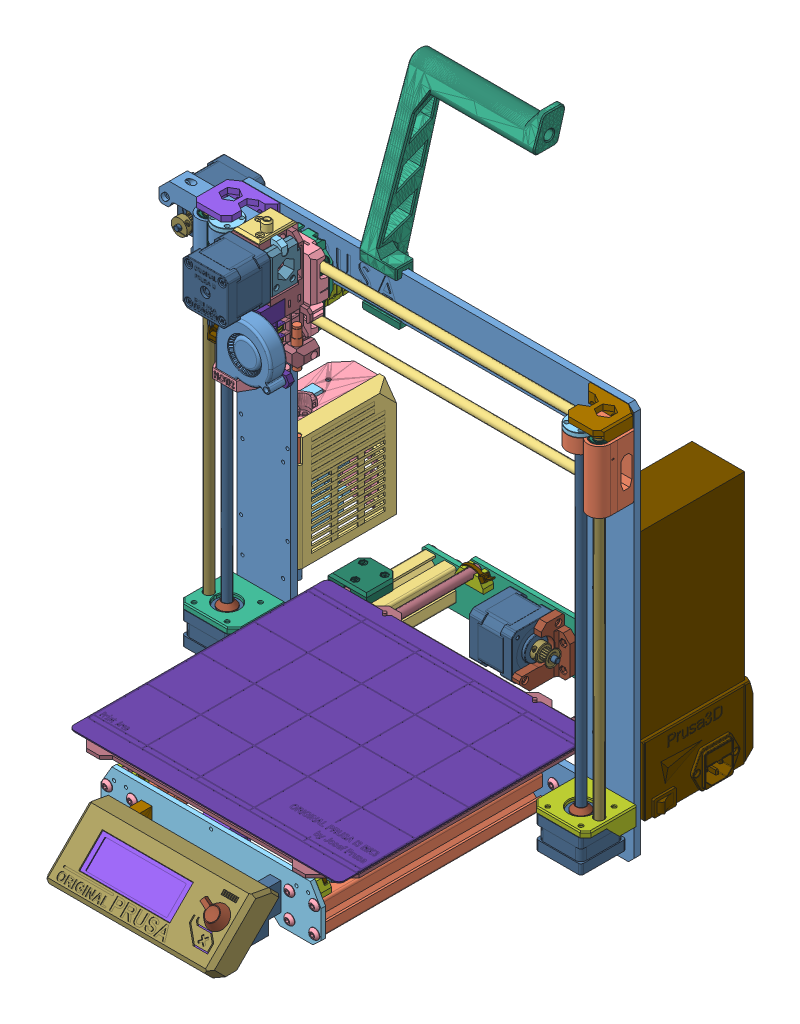
SolidWorks assembly Prusa i3 MK3, configuration Default. Lengths in mm.
Overall size (428.7 559.98 435.12).
133 component instances, 60 part files, 144 mates.
Components (placement in the parent):
- Frame Assembly-1: Frame Assembly [Default] at (46.7331 -29.8101 -38.614) size (370 375 345.6)
  - i3 MK3 Frame-1: i3 MK3 Frame [Default] at (-79.4742 52.1894 268.1135) size (370 370 6.25)
  - Long Extrusion-1: Long Extrusion [Default] at (190.5258 68.6894 274.3635) size (30 30 205)
  - Long Extrusion-2: Long Extrusion [Default] at (20.5258 68.6894 274.3635) size (30 30 205)
  - Short Extrusion-1: Short Extrusion [Default] at (-16.4742 68.6894 148.1135) size (30 30 120)
  - Short Extrusion-2: Short Extrusion [Default] at (227.5258 68.6894 148.1135) size (30 30 120)
  - M5-16 Caphead Screw-1: M5-16 Caphead Screw [92095A212] at (239.1258 57.0894 277.1135) size (9.5 9.5 19.24)
  - M5-16 Caphead Screw-2: M5-16 Caphead Screw [92095A212] at (8.9287 80.3027 486.3635) size (9.5 9.5 19.24)
  - M5-16 Caphead Screw-3: M5-16 Caphead Screw [92095A212] at (202.1295 80.303 486.3635) size (9.5 9.5 19.24)
  - M5-16 Caphead Screw-4: M5-16 Caphead Screw [92095A212] at (178.9311 80.3021 486.3635) size (9.5 9.5 19.24)
  - M5-16 Caphead Screw-5: M5-16 Caphead Screw [92095A212] at (215.9258 80.2894 277.1135) size (9.5 9.5 19.24)
  - M5-16 Caphead Screw-6: M5-16 Caphead Screw [92095A212] at (8.9258 57.0894 486.3635) size (9.5 9.5 19.24)
  - M5-16 Caphead Screw-7: M5-16 Caphead Screw [92095A212] at (178.9324 57.0896 486.3635) size (9.5 9.5 19.24)
  - M5-16 Caphead Screw-8: M5-16 Caphead Screw [92095A212] at (239.1258 80.2894 277.1135) size (9.5 9.5 19.24)
  - M5-16 Caphead Screw-9: M5-16 Caphead Screw [92095A212] at (202.1324 57.0896 486.3635) size (9.5 9.5 19.24)
  - M5-16 Caphead Screw-10: M5-16 Caphead Screw [92095A212] at (32.1258 57.0894 486.3635) size (9.5 9.5 19.24)
  - M5-16 Caphead Screw-11: M5-16 Caphead Screw [92095A212] at (32.127 80.3019 486.3635) size (9.5 9.5 19.24)
  - M5-16 Caphead Screw-12: M5-16 Caphead Screw [92095A212] at (-4.8742 80.2894 277.1135) size (9.5 9.5 19.24)
  - M5-16 Caphead Screw-13: M5-16 Caphead Screw [92095A212] at (-4.8742 57.0894 277.1135) size (9.5 9.5 19.24)
  - M5-16 Caphead Screw-14: M5-16 Caphead Screw [92095A212] at (-28.0742 80.2894 277.1135) size (9.5 9.5 19.24)
  - M5-16 Caphead Screw-15: M5-16 Caphead Screw [92095A212] at (-28.0742 57.0894 277.1135) size (9.5 9.5 19.24)
  - M5-16 Caphead Screw-16: M5-16 Caphead Screw [92095A212] at (215.9258 57.0894 277.1135) size (9.5 9.5 19.24)
  - M5-16 Caphead Screw-17: M5-16 Caphead Screw [92095A212] at (215.9258 80.2894 141.1135) x (1 0 0) z (0 0 -1) size (9.5 9.5 19.24)
  - M5-16 Caphead Screw-18: M5-16 Caphead Screw [92095A212] at (32.1258 80.2894 265.3635) x (1 0 0) z (0 0 -1) size (9.5 9.5 19.24)
  - M5-16 Caphead Screw-19: M5-16 Caphead Screw [92095A212] at (202.1258 80.2894 265.3635) x (1 0 0) z (0 0 -1) size (9.5 9.5 19.24)
  - M5-16 Caphead Screw-20: M5-16 Caphead Screw [92095A212] at (178.9258 80.2894 265.3635) x (1 0 0) z (0 0 -1) size (9.5 9.5 19.24)
  - M5-16 Caphead Screw-21: M5-16 Caphead Screw [92095A212] at (215.926 57.0893 141.1135) x (1 0 0) z (0 0 -1) size (9.5 9.5 19.24)
  - M5-16 Caphead Screw-22: M5-16 Caphead Screw [92095A212] at (8.9258 57.0894 265.3635) x (1 0 0) z (0 0 -1) size (9.5 9.5 19.24)
  - M5-16 Caphead Screw-23: M5-16 Caphead Screw [92095A212] at (8.9258 80.2894 265.3635) x (1 0 0) z (0 0 -1) size (9.5 9.5 19.24)
  - M5-16 Caphead Screw-24: M5-16 Caphead Screw [92095A212] at (239.1258 80.2894 141.1135) x (1 0 0) z (0 0 -1) size (9.5 9.5 19.24)
  - M5-16 Caphead Screw-25: M5-16 Caphead Screw [92095A212] at (239.1259 57.0892 141.1135) x (1 0 0) z (0 0 -1) size (9.5 9.5 19.24)
  - M5-16 Caphead Screw-26: M5-16 Caphead Screw [92095A212] at (-4.8712 80.276 141.1135) x (1 0 0) z (0 0 -1) size (9.5 9.5 19.24)
  - M5-16 Caphead Screw-27: M5-16 Caphead Screw [92095A212] at (-28.0743 80.2892 141.1135) x (1 0 0) z (0 0 -1) size (9.5 9.5 19.24)
  - M5-16 Caphead Screw-28: M5-16 Caphead Screw [92095A212] at (-28.072 57.0752 141.1135) x (1 0 0) z (0 0 -1) size (9.5 9.5 19.24)
  - M5-16 Caphead Screw-29: M5-16 Caphead Screw [92095A212] at (-4.874 57.0894 141.1135) x (1 0 0) z (0 0 -1) size (9.5 9.5 19.24)
  - M5-16 Caphead Screw-30: M5-16 Caphead Screw [92095A212] at (178.9258 57.0894 265.3635) x (1 0 0) z (0 0 -1) size (9.5 9.5 19.24)
  - M5-16 Caphead Screw-31: M5-16 Caphead Screw [92095A212] at (202.1258 57.0894 265.3635) x (1 0 0) z (0 0 -1) size (9.5 9.5 19.24)
  - M5-16 Caphead Screw-32: M5-16 Caphead Screw [92095A212] at (32.1258 57.0894 265.3635) x (1 0 0) z (0 0 -1) size (9.5 9.5 19.24)
  - MK3 Front Plate-1: MK3 Front Plate [Default] at (105.5324 47.1896 479.3635) x (-1 0 0) z (0 0 1) size (205 50 4.25)
  - MK3 Rear Plate-1: MK3 Rear Plate [Default] at (105.526 50.1894 143.8635) size (278 50 4.25)
- y-rod-holder(R2)-1: y-rod-holder(R2) [Default] at (67.2591 53.8793 109.4995) x (-1 0 0) z (0 0 1) size (26 13.5 10)
- y-rod-holder(R2)-2: y-rod-holder(R2) [Default] at (237.2591 53.8793 109.4995) x (-1 -0.000001 0) z (0 0 1) size (26 13.5 10)
- y-rod-holder(R2)-3: y-rod-holder(R2) [Default] at (67.2588 53.8793 440.7495) x (1 0.000003 0) z (0 0 -1) size (26 13.5 10)
- y-rod-holder(R2)-4: y-rod-holder(R2) [Default] at (237.2655 53.8796 440.7495) x (1 0 0) z (0 0 -1) size (26 13.5 10)
- y-belt-idler(R2)-1: y-belt-idler(R2) [Default] at (152.2622 27.3871 440.7495) x (-1 -0.000001 0) z (-0.000001 1 0) size (25 20 35)
- Idler Roller, flat-1: Idler Roller, flat [Default] at (147.9121 49.8871 426.7495) x (0 0 -1) z (1 0.000001 0) size (18 18 8.83)
- NEMA-17 40mm PR-1: NEMA-17 40mm PR [По умолчанию] at (99.2666 46.3725 130.4995) x (0 0 -1) z (0 -1 0) size (42.3 62 51.35)
- y-motor-holder(R2)-1: y-motor-holder(R2) [Default] at (152.2666 20.3725 110.9995) x (-1 0 0) z (0 1 0) size (19 42 47)
- PULLEY_GT2_16T-1: PULLEY_GT2_16T [Default] at (148.5591 46.3725 130.4995) x (0 -0.177583 0.984106) z (-1 0 0) size (14.7 14.7 14.3)
- Y-Smooth Rod-1: Y-Smooth Rod [Default] at (67.2588 64.3793 110.7495) size (8 8 330)
- Frog Assembly-1: Frog Assembly [Default] at (70.8506 199.1097 499.2992) x (1 0 0) z (0 0 -1) size (227 34.1 222)
  - i3 MK3 Frog-1: i3 MK3 Frog [Default] at (-100.0918 124.8902 356.7011) size (227 4.25 222)
  - LM8UU-1: LM8UU [Default] at (166.4082 134.7303 172.4511) x (0 0 -1) z (0.49499 0.868899 0) size (24 15 15)
  - LM8UU-2: LM8UU [Default] at (-3.5918 134.7303 205.9511) x (0 0 -1) z (0.957162 -0.289554 0) size (24 15 15)
  - LM8UU-3: LM8UU [Default] at (-3.5918 134.7303 135.9511) x (0 0 -1) z (-0.936768 -0.349951 0) size (24 15 15)
  - y-belt-holder(R2)-1: y-belt-holder(R2) [Default] at (88.4082 141.6402 171.2011) x (0 -1 0) z (-1 0 0) size (23.5 48 14)
  - U Bolt-1: U Bolt [Default] at (166.4082 118.7303 171.7011) size (23.09 26.7 3.46)
  - U Bolt-2: U Bolt [Default] at (-3.5918 118.7303 136.7011) size (23.09 26.7 3.46)
  - U Bolt-3: U Bolt [Default] at (-3.5918 118.7303 206.7011) size (23.09 26.7 3.46)
- Y-Smooth Rod-2: Y-Smooth Rod [Default] at (237.2655 64.3796 110.7495) size (8 8 330)
- Y Holder Ziptie-1: Y Holder Ziptie [Default] at (237.2655 53.8796 434.0495) size (30.19 10 6)
- Y Holder Ziptie-2: Y Holder Ziptie [Default] at (237.1042 53.8796 116.1995) x (1 0.000001 0) z (0 0 1) size (30.19 10 6)
- Y Holder Ziptie-3: Y Holder Ziptie [Default] at (67.4135 53.8793 434.0495) x (-1 -0.000003 0) z (0 0 -1) size (30.19 10 6)
- Y Holder Ziptie-4: Y Holder Ziptie [Default] at (67.2591 53.8793 116.1995) x (-1 0 0) z (0 0 -1) size (30.19 10 6)
- x_end_motor_R2_part-1: x_end_motor_R2_part [Default] at (-29.7411 380.6793 265.0495) x (0 0 1) z (0 -1 0) size (36.12 82.62 58)
- x-end-idler(R2)-1: x-end-idler(R2) [Default] at (355.2589 380.6793 265.0495) x (0 0 1) z (0 -1 0) size (36.12 40.12 58)
- X-Smooth Rod-1: X-Smooth Rod [Default] at (-36.7411 374.6793 250.0495) x (0 0 -1) z (1 0 0) size (8 8 370)
- X-Smooth Rod-2: X-Smooth Rod [Default] at (-36.7411 329.6793 250.0495) x (0 0 -1) z (1 0 0) size (8 8 370)
- LM8UU-1: LM8UU [Default] at (-29.7411 368.6793 265.0495) x (0 1 0) z (0 0 1) size (24 15 15)
- LM8UU-2: LM8UU [Default] at (334.2589 334.6793 265.0495) x (0 1 0) z (0 0 1) size (24 15 15)
- LM8UU-3: LM8UU [Default] at (-29.7411 335.2793 265.0495) x (0 1 0) z (0 0 1) size (24 15 15)
- LM8UU-4: LM8UU [Default] at (334.2589 368.6793 265.0495) x (0 1 0) z (-0.546944 0 0.837169) size (24 15 15)
- LM8UU-5: LM8UU [Default] at (24.8458 374.6793 250.0495) size (24 15 15)
- LM8UU-6: LM8UU [Default] at (37.3458 329.6793 250.0495) size (24 15 15)
- LM8UU-7: LM8UU [Default] at (48.8458 374.6793 250.0495) size (24 15 15)
- NEMA-17 40mm PR-2: NEMA-17 40mm PR [По умолчанию] at (-61.7411 350.4293 201.5495) x (1 0 0) z (0 -1 0) size (42.3 62 51.35)
- PULLEY_GT2_16T-2: PULLEY_GT2_16T [Default] at (-61.7411 350.4293 254.7495) x (0.994167 -0.107852 0) z (0 0 1) size (14.7 14.7 14.3)
- x-carriage(R2)-1: x-carriage(R2) [Default] at (21.3458 329.6793 262.0495) x (-1 0 0) z (0 0 -1) size (52 90 15)
- Idler Roller, flat-2: Idler Roller, flat [Default] at (318.7589 350.4293 246.6995) size (18 18 8.83)
- Z_NUT-1: Z_NUT [Default] at (-12.7411 384.6793 265.0495) x (0.707107 0 -0.707107) z (0.707107 0 0.707107) size (25 10 25)
- Z_NUT-2: Z_NUT [Default] at (317.2589 384.6793 265.0495) x (0.707107 0 0.707107) z (-0.707107 0 0.707107) size (25 10 25)
- z-axis-bottom-left(R2)-1: z-axis-bottom-left(R2) [Default] at (-45.7411 74.1793 235.7495) x (0 0 1) z (0 -1 0) size (50 52.5 36)
- z-axis-bottom-right(R2)-1: z-axis-bottom-right(R2) [Default] at (337.2589 74.1793 235.7495) x (0 0 1) z (0 -1 0) size (50 52.5 36)
- z-axis-top-left(R2)-1: z-axis-top-left(R2) [Default] at (-42.7411 392.1793 235.7495) x (0 0 1) z (0 -1 0) size (38 45 16)
- z-axis-top-right(R2)-1: z-axis-top-right(R2) [Default] at (337.2589 392.1793 235.7495) x (0 0 1) z (0 -1 0) size (38 45 16)
- MOTOR_NEMA17_W_THREADED_SHAFT-1: MOTOR_NEMA17_W_THREADED_SHAFT [Default] at (-12.7411 54.1793 265.0495) x (0 0 -1) z (0 1 0) size (47.3 42.3 350)
- MOTOR_NEMA17_W_THREADED_SHAFT-2: MOTOR_NEMA17_W_THREADED_SHAFT [Default] at (317.2589 54.1793 265.0495) x (0 0 -1) z (0 1 0) size (47.3 42.3 350)
- z-screw-cover-1: z-screw-cover [Default] at (-12.7411 71.1793 265.0495) x (1 0 0) z (0 1 0) size (16 16 5)
- z-screw-cover-2: z-screw-cover [Default] at (317.2589 71.1793 265.0495) x (1 0 0) z (0 1 0) size (16 16 5)
- Z-Smooth Rod-1: Z-Smooth Rod [Default] at (-29.7411 389.1793 265.0495) x (1 0 0) z (0 -1 0) size (8 8 320)
- Z-Smooth Rod-2: Z-Smooth Rod [Default] at (334.2589 389.1793 265.0495) x (1 0 0) z (0 -1 0) size (8 8 320)
- Extruder Assembly-1: Extruder Assembly [Default] at (24.1055 296.0339 201.1728) size (76.41 114.5 76)
  - extruder-body(R2)-1: extruder-body(R2) [Default] at (14.2402 58.6454 60.8767) x (-1 0 0) z (0 0 -1) size (63.5 95 30.5)
  - extruder-idler(R2)-1: extruder-idler(R2) [Default] at (14.2402 58.6454 59.3767) x (0 0 1) z (-1 0 0) size (28 34 17)
  - idler pulley shaft-1: idler pulley shaft [Default] at (18.2402 85.6454 62.1267) size (3 3 24)
  - NEMA-17 40mm PR-1: NEMA-17 40mm PR [По умолчанию] at (10.2402 85.6454 131.3767) x (-1 0 0) z (0 -1 0) size (42.3 62 51.35)
  - E3D V6-1: E3D V6 [Default] at (14.2402 48.5454 77.8767) x (1 0 0) z (0 -1 0) size (21.69 25.84 58.6)
  - extruder-cover(R2)-1: extruder-cover(R2) [Default] at (14.2402 58.6454 60.8767) x (-1 0 0) z (0 0 -1) size (75.15 49.75 23.94)
  - Noctua-NF-A4x10-1: Noctua-NF-A4x10 [Default] at (-12.2589 37.0799 80.8112) x (0 -1 0) z (-1 0 0) size (40.06 40.06 12.26)
  - FAN_5015_BLOWER-1: FAN_5015_BLOWER [Default] at (31.7402 38.1454 116.2767) x (0 -1 0) z (1 0 0) size (51.75 17.19 52.1)
  - PINDA Probe-1: PINDA Probe [Default] at (37.2402 32.9116 72.8767) x (1 0 0) z (0 -1 0) size (7.8 7.8 35.75)
  - filament-sensor-cover-1: filament-sensor-cover [Default] at (14.2402 58.6454 60.8767) x (-1 0 0) z (0 0 -1) size (24 11.5 36)
  - nozzle-fan-1: nozzle-fan [Default] at (14.2402 58.6454 65.3767) x (-1 0 0) z (0 0 -1) size (47.83 17 42)
  - extruder-idler-plug-1: extruder-idler-plug [Default] at (13.8402 58.6454 59.3767) x (-1 0 0) z (0 0 -1) size (10.6 10.3 5.6)
- x-carriage-back(R2)-1: x-carriage-back(R2) [Default] at (38.3458 354.6793 262.1495) x (-1 0 0) z (0 0 -1) size (52 73.5 8)
- cable-holder-1: cable-holder [Default] at (38.3458 354.6793 263.0495) x (-1 0 0) z (0 0 -1) size (10 17.91 39.5)
- LCD Assembly-1: LCD Assembly [Default] at (106.2916 -100.65 474.1347) x (1 0 0) z (0 0.707107 0.707107) size (155 84.29 80.03)
  - LCD Board-1: LCD Board [Default] at (45.5138 89.6171 111.3378) size (150 63 29.71)
  - lcd-supports1-1: lcd-supports1 [Default] at (-9.0362 59.8671 105.6378) x (0 -0.707107 0.707107) z (-1 0 0) size (65.69 47.48 20)
  - lcd-supports2-1: lcd-supports2 [Default] at (110.9738 59.8671 105.6378) x (0 -0.707107 0.707107) z (-1 0 0) size (65.69 47.48 10)
  - LCD-KNOB-1: LCD-KNOB [Default] at (104.2929 89.8433 126.2378) x (-0.386654 -0.922225 0) z (0 0 1) size (20 27.64 8.79)
  - LCD-cover-ORIGINAL-MK3(R2)-1: LCD-cover-ORIGINAL-MK3(R2) [Default] at (45.2638 108.0671 124.7378) x (1 0 0) z (0 0 -1) size (155 70 26.06)
- Headbed Assembly-1: Headbed Assembly [Default] at (88.2608 -72.955 114.9048) size (253.8 13.6 281.4)
  - MK52 Bed-1: MK52 Bed [Default] at (-64.502 153.1745 327.7347) size (253.8 6 264.25)
  - 6x6x3t spacer-1: 6x6x3t spacer [Default] at (62.498 147.1745 212.6933) size (6 6 6)
  - 6x6x3t spacer-2: 6x6x3t spacer [Default] at (62.498 147.1745 107.6933) size (6 6 6)
  - 6x6x3t spacer-3: 6x6x3t spacer [Default] at (-47.502 147.1745 317.6933) size (6 6 6)
  - 6x6x3t spacer-4: 6x6x3t spacer [Default] at (-47.502 147.1745 107.6933) x (0.97497 0 -0.222336) z (0.222336 0 0.97497) size (6 6 6)
  - 6x6x3t spacer-5: 6x6x3t spacer [Default] at (167.498 147.1745 317.6933) size (6 6 6)
  - 6x6x3t spacer-6: 6x6x3t spacer [Default] at (167.498 147.1745 212.6933) size (6 6 6)
  - 6x6x3t spacer-7: 6x6x3t spacer [Default] at (167.498 147.1745 107.6933) x (0.999855 0 0.017002) z (-0.017002 0 0.999855) size (6 6 6)
  - 6x6x3t spacer-8: 6x6x3t spacer [Default] at (62.498 147.1745 317.6933) size (6 6 6)
  - 6x6x3t spacer-9: 6x6x3t spacer [Default] at (-47.502 147.1745 212.6933) size (6 6 6)
  - heatbed-cable-cover top-1: heatbed-cable-cover top [Default] at (-46.0021 152.1745 93.2347) x (1 0 0) z (0 1 0) size (36 32 8.6)
  - heatbed-cable-cover bottom-1: heatbed-cable-cover bottom [Default] at (-46.0021 157.6745 113.2347) x (-1 0 0) z (0 -1 0) size (30 16.5 6)
  - SS Sheet-1: SS Sheet [Default] at (-63.6476 156.1745 335.43) size (252 1.01 241)
- PSU-1: PSU [Default] at (284.7589 53.8793 227.9995) x (0 0 -1) z (1 0 0) size (103 233 79.05)
- Einsy-hinges2-1: Einsy-hinges2 [Default] at (18.6589 86.1793 224.4995) x (0 0 -1) z (0 1 0) size (7.8 13.8 17)
- Einsy-hinges1-1: Einsy-hinges1 [Default] at (12.6589 201.1793 224.4995) x (0 0 -1) z (0 -1 0) size (7.4 13.4 28)
- einsey-doors-1: einsey-doors [Default] at (17.1589 201.6793 136.9995) x (0 -1 0) z (-1 0 0) size (105.5 92 16.29)
- Einsy-base-1: Einsy-base [Default] at (-32.8339 200.6796 229.4995) x (-0.000069 -1 0) z (1 -0.000069 0) size (127.5 92 38)
- Einsy_Rambo-1: Einsy_Rambo [Default] at (-23.241 175.7001 163.4002) x (-0.000069 -1 0) z (1 -0.000069 0) size (108.28 71 21.5)
- Spool-holder-1: Spool-holder [Default] at (86.205 379.5108 561.5962) x (0 0 -1) z (1 0 0) size (72.27 192.64 120.6)
Mates (geometry in assembly coordinates):
- Coincident1: coincident anti-aligned: plane of Frame Assembly-1/MK3 Front Plate-1 through (152.2655 17.3796 440.7495) normal (0 0 -1); plane of y-rod-holder(R2)-3 through (54.2588 53.8793 440.7495) normal (0 0 1)
- Coincident2: coincident anti-aligned: plane of Frame Assembly-1/MK3 Front Plate-1 through (152.2655 17.3796 440.7495) normal (0 0 -1); plane of y-rod-holder(R2)-4 through (224.2655 53.8796 440.7495) normal (0 0 1)
- Concentric1: concentric anti-aligned: circle of Frame Assembly-1/MK3 Front Plate-1; cone of y-rod-holder(R2)-4 through (242.7655 57.3796 440.7495) axis (0 0 -1)
- Concentric2: concentric aligned: circle of Frame Assembly-1/MK3 Front Plate-1; circle of y-rod-holder(R2)-4
- Concentric3: concentric aligned: circle of Frame Assembly-1/MK3 Front Plate-1; circle of y-rod-holder(R2)-3
- Concentric4: concentric aligned: circle of Frame Assembly-1/MK3 Front Plate-1; circle of y-rod-holder(R2)-3
- Coincident4: coincident anti-aligned: plane of Frame Assembly-1/MK3 Rear Plate-1 through (152.2591 20.3793 109.4995) normal (0 0 1); plane of y-rod-holder(R2)-2 through (250.2591 53.8794 109.4995) normal (0 0 -1)
- Coincident5: coincident anti-aligned: plane of Frame Assembly-1/MK3 Rear Plate-1 through (152.2591 20.3793 109.4995) normal (0 0 1); plane of y-rod-holder(R2)-1 through (80.2591 53.8793 109.4995) normal (0 0 -1)
- Concentric5: concentric anti-aligned: circle of Frame Assembly-1/MK3 Rear Plate-1; cylinder of y-rod-holder(R2)-1 through (61.7591 57.3793 118.4995) axis (0 0 -1) radius 1.6
- Concentric9: concentric aligned: cylinder of Frame Assembly-1/MK3 Rear Plate-1 through (231.7591 57.3793 109.4995) axis (0 0 -1) radius 1.5; circle of y-rod-holder(R2)-2
- Concentric10: concentric aligned: cylinder of Frame Assembly-1/MK3 Rear Plate-1 through (242.7591 57.3793 109.4995) axis (0 0 -1) radius 1.5; circle of y-rod-holder(R2)-2
- Parallel1: parallel aligned: plane of Frame Assembly-1/MK3 Rear Plate-1 through (245.2591 67.3793 109.4995) normal (0 1 0); plane of y-rod-holder(R2)-1 through (80.2591 65.8793 109.4995) normal (0 1 0)
- Coincident7: coincident anti-aligned: plane of y-belt-idler(R2)-1 through (152.2622 27.3871 440.7495) normal (-1 -0.000001 0); plane of Idler Roller, flat-1 through (152.2621 49.8871 426.7495) normal (1 0.000001 0)
- Concentric11: concentric anti-aligned: cylinder of y-belt-idler(R2)-1 through (144.2621 49.8871 426.7495) axis (-1 -0.000001 0) radius 3.1; cylinder of Idler Roller, flat-1 through (147.9111 49.8871 426.7495) axis (1 0.000001 0) radius 2.5
- Coincident8: coincident anti-aligned: plane of Frame Assembly-1/MK3 Front Plate-1 through (152.2655 17.3796 440.7495) normal (0 0 -1); plane of y-belt-idler(R2)-1 through (164.7622 32.3871 440.7495) normal (0 0 1)
- Concentric12: concentric aligned: circle of Frame Assembly-1/MK3 Front Plate-1; circle of y-belt-idler(R2)-1
- Concentric13: concentric anti-aligned: cylinder of Frame Assembly-1/MK3 Front Plate-1 through (152.2622 37.387 444.9995) axis (0 0 -1) radius 1.5; circle of y-belt-idler(R2)-1
- Coincident9: coincident anti-aligned: plane of NEMA-17 40mm PR-1 through (139.2666 46.3725 130.4995) normal (1 0 0); plane of y-motor-holder(R2)-1 through (139.2666 20.3725 109.4995) normal (-1 0 0)
- Concentric14: concentric aligned: circle of NEMA-17 40mm PR-1; cylinder of y-motor-holder(R2)-1 through (148.2666 61.8725 114.9995) axis (-1 0 0) radius 3.1
- Concentric15: concentric aligned: circle of NEMA-17 40mm PR-1; circle of y-motor-holder(R2)-1
- Coincident10: coincident anti-aligned: plane of Frame Assembly-1/MK3 Rear Plate-1 through (152.2591 20.3793 109.4995) normal (0 0 1); plane of y-motor-holder(R2)-1 through (158.2666 20.3725 109.4995) normal (0 0 -1)
- Concentric16: concentric anti-aligned: circle of Frame Assembly-1/MK3 Rear Plate-1; cylinder of y-motor-holder(R2)-1 through (152.2666 27.3725 122.9995) axis (0 0 -1) radius 1.6
- Parallel2: parallel aligned: plane of Frame Assembly-1/MK3 Rear Plate-1 through (245.2591 67.3793 109.4995) normal (0 1 0); plane of y-motor-holder(R2)-1 through (158.2666 67.3725 109.4995) normal (0 1 0)
- Concentric19: concentric anti-aligned: cylinder of NEMA-17 40mm PR-1 through (161.2666 46.3725 130.4995) axis (-1 0 0) radius 2.5; cylinder of PULLEY_GT2_16T-1 through (142.2591 46.3725 130.4995) axis (1 0 0) radius 2.5
- Coincident15: coincident aligned: plane of Frame Assembly-1/MK3 Rear Plate-1 through (152.2591 20.3793 105.2495) normal (1 0 0); plane of PULLEY_GT2_16T-1 through (152.2591 46.3725 130.4995) normal (1 0 0)
- Concentric20: concentric anti-aligned: cylinder of y-rod-holder(R2)-3 through (67.2588 64.3793 429.7495) axis (0 0 1) radius 4; cylinder of Y-Smooth Rod-1 through (67.2588 64.3793 440.7495) axis (0 0 -1) radius 4
- Coincident16: coincident anti-aligned: plane of Frame Assembly-1/MK3 Front Plate-1 through (152.2655 17.3796 440.7495) normal (0 0 -1); plane of Y-Smooth Rod-1 through (67.2588 64.3793 440.7495) normal (0 0 1)
- Concentric21: concentric anti-aligned: cylinder of y-rod-holder(R2)-4 through (237.2655 64.3796 429.7495) axis (0 0 1) radius 4; cylinder of Y-Smooth Rod-2 through (237.2655 64.3796 440.7495) axis (0 0 -1) radius 4
- Coincident17: coincident anti-aligned: plane of Frame Assembly-1/MK3 Front Plate-1 through (152.2655 17.3796 440.7495) normal (0 0 -1); plane of Y-Smooth Rod-2 through (237.2655 64.3796 440.7495) normal (0 0 1)
- Concentric22: concentric aligned: cylinder of Y-Smooth Rod-1 through (67.2588 64.3793 440.7495) axis (0 0 -1) radius 4; cylinder of Frog Assembly-1/LM8UU-3 through (67.2588 64.3793 317.6586) axis (0 0 -1) radius 4
- Parallel3: parallel aligned: plane of Frame Assembly-1/i3 MK3 Frame-1 through (-32.7411 58.8793 235.7495) normal (0 1 0); plane of Frog Assembly-1/i3 MK3 Frog-1 through (-29.2412 74.2195 142.5981) normal (0 1 0)
- Tangent2: tangent aligned: cylinder of Y-Smooth Rod-2 through (237.2655 64.3796 440.7495) axis (0 0 -1) radius 4; cylinder of Y Holder Ziptie-1 through (237.3428 54.524 435.5495) axis (0 0 -1) radius 13.8558
- Coincident20: coincident anti-aligned: plane of y-rod-holder(R2)-4 through (238.0655 78.3796 435.5495) normal (0.866025 0.5 0); plane of Y Holder Ziptie-1 through (248.4743 60.351 435.5495) normal (-0.866025 -0.5 0)
- Coincident21: coincident anti-aligned: plane of y-rod-holder(R2)-4 through (245.0655 62.8796 435.5495) normal (0 0 -1); plane of Y Holder Ziptie-1 through (237.2655 53.8796 435.5495) normal (0 0 1)
- Coincident22: coincident anti-aligned: plane of y-rod-holder(R2)-3 through (67.1908 79.3793 435.5495) normal (-0.866027 0.499998 0); plane of Y Holder Ziptie-3 through (56.2047 60.3507 432.5495) normal (0.866027 -0.499998 0)
- Coincident23: coincident anti-aligned: plane of y-rod-holder(R2)-3 through (75.0588 62.8794 435.5495) normal (0 0 -1); plane of Y Holder Ziptie-3 through (67.4135 53.8793 435.5495) normal (0 0 1)
- Tangent3: tangent aligned: cylinder of Y-Smooth Rod-1 through (67.2588 64.3793 440.7495) axis (0 0 -1) radius 4; cylinder of Y Holder Ziptie-3 through (67.3361 54.5238 432.5495) axis (0 0 1) radius 13.8558
- Tangent4: tangent aligned: cylinder of Y-Smooth Rod-1 through (67.2588 64.3793 440.7495) axis (0 0 -1) radius 4; cylinder of Y Holder Ziptie-4 through (67.1817 54.5238 114.6995) axis (0 0 1) radius 13.8558
- Tangent5: tangent aligned: cylinder of Y-Smooth Rod-2 through (237.2655 64.3796 440.7495) axis (0 0 -1) radius 4; cylinder of Y Holder Ziptie-2 through (237.1816 54.5241 117.6995) axis (0 0 -1) radius 13.8558
- Coincident24: coincident anti-aligned: plane of y-rod-holder(R2)-1 through (66.4591 78.3793 114.6995) normal (-0.866025 0.5 0); plane of Y Holder Ziptie-4 through (56.0503 60.3507 114.6995) normal (0.866025 -0.5 0)
- Coincident25: coincident anti-aligned: plane of y-rod-holder(R2)-1 through (59.4591 62.8793 114.6995) normal (0 0 1); plane of Y Holder Ziptie-4 through (67.2591 53.8793 114.6995) normal (0 0 -1)
- Coincident26: coincident anti-aligned: plane of y-rod-holder(R2)-2 through (237.327 79.3793 114.6995) normal (0.866025 0.500001 0); plane of Y Holder Ziptie-2 through (248.313 60.351 117.6995) normal (-0.866025 -0.500001 0)
- Coincident27: coincident anti-aligned: plane of y-rod-holder(R2)-2 through (229.4591 62.8793 114.6995) normal (0 0 1); plane of Y Holder Ziptie-2 through (237.1042 53.8796 114.6995) normal (0 0 -1)
- Concentric23: concentric anti-aligned: cylinder of x-end-idler(R2)-1 through (292.7589 329.6793 250.0495) axis (1 0 0) radius 4.0764; cylinder of X-Smooth Rod-2 through (333.2589 329.6793 250.0495) axis (-1 0 0) radius 4
- Concentric24: concentric anti-aligned: cylinder of x-end-idler(R2)-1 through (293.2589 374.6793 250.0495) axis (1 0 0) radius 4.0764; cylinder of X-Smooth Rod-1 through (333.2589 374.6793 250.0495) axis (-1 0 0) radius 4
- Coincident28: coincident aligned: plane of X-Smooth Rod-1 through (-36.7411 374.6793 250.0495) normal (-1 0 0); plane of X-Smooth Rod-2 through (-36.7411 329.6793 250.0495) normal (-1 0 0)
- Concentric25: concentric anti-aligned: circle of x_end_motor_R2_part-1; cylinder of X-Smooth Rod-1 through (333.2589 374.6793 250.0495) axis (-1 0 0) radius 4
- Coincident29: coincident anti-aligned: plane of x-end-idler(R2)-1 through (333.2589 374.6793 250.0495) normal (-1 0 0); plane of X-Smooth Rod-1 through (333.2589 374.6793 250.0495) normal (1 0 0)
- Concentric27: concentric aligned: cylinder of LM8UU-1 through (-29.7411 322.9898 265.0495) axis (0 -1 0) radius 7.5; cylinder of LM8UU-3 through (-29.7411 289.5898 265.0495) axis (0 -1 0) radius 7.5
- Concentric28: concentric aligned: cylinder of LM8UU-2 through (334.2589 288.9898 265.0495) axis (0 -1 0) radius 7.5; cylinder of LM8UU-4 through (334.2589 322.9898 265.0495) axis (0 -1 0) radius 7.5
- Concentric29: concentric anti-aligned: circle of x_end_motor_R2_part-1; cylinder of LM8UU-3 through (-29.7411 289.5898 265.0495) axis (0 -1 0) radius 7.5
- Coincident30: coincident aligned: circle of x_end_motor_R2_part-1; plane of LM8UU-3 through (-29.7411 323.2793 265.0495) normal (0 -1 0)
- Coincident31: coincident aligned: plane of x_end_motor_R2_part-1 through (-29.7411 380.6793 265.0495) normal (0 1 0); plane of LM8UU-1 through (-29.7411 380.6793 265.0495) normal (0 1 0)
- Concentric30: concentric aligned: cylinder of x-end-idler(R2)-1 through (334.2589 381.6793 265.0495) axis (0 -1 0) radius 7.5408; cylinder of LM8UU-2 through (334.2589 288.9898 265.0495) axis (0 -1 0) radius 7.5
- Coincident32: coincident aligned: plane of x-end-idler(R2)-1 through (334.2589 322.6793 265.0495) normal (0 -1 0); plane of LM8UU-2 through (334.2589 322.6793 265.0495) normal (0 -1 0)
- Coincident33: coincident aligned: plane of x-end-idler(R2)-1 through (334.2589 380.6793 265.0495) normal (0 1 0); plane of LM8UU-4 through (334.2589 380.6793 265.0495) normal (0 1 0)
- Concentric31: concentric anti-aligned: circle of x_end_motor_R2_part-1; cylinder of X-Smooth Rod-2 through (333.2589 329.6793 250.0495) axis (-1 0 0) radius 4
- Concentric32: concentric aligned: cylinder of X-Smooth Rod-1 through (333.2589 374.6793 250.0495) axis (-1 0 0) radius 4; cylinder of LM8UU-5 through (-20.8438 374.6793 250.0495) axis (-1 0 0) radius 7.5
- Concentric33: concentric aligned: cylinder of X-Smooth Rod-1 through (333.2589 374.6793 250.0495) axis (-1 0 0) radius 4; cylinder of LM8UU-7 through (3.1562 374.6793 250.0495) axis (-1 0 0) radius 7.5
- Concentric34: concentric aligned: cylinder of X-Smooth Rod-2 through (333.2589 329.6793 250.0495) axis (-1 0 0) radius 4; cylinder of LM8UU-6 through (-8.3438 329.6793 250.0495) axis (-1 0 0) radius 7.5
- Concentric35: concentric aligned: cylinder of NEMA-17 40mm PR-2 through (-61.7411 350.4293 263.5495) axis (0 0 -1) radius 2.5; cylinder of PULLEY_GT2_16T-2 through (-61.7411 350.4293 261.0495) axis (0 0 -1) radius 7.35
- Coincident34: coincident anti-aligned: plane of x_end_motor_R2_part-1 through (-1.2411 380.6793 241.5495) normal (0 0 -1); plane of NEMA-17 40mm PR-2 through (-61.7411 350.4293 241.5495) normal (0 0 1)
- Concentric36: concentric aligned: cone of x_end_motor_R2_part-1 through (-46.2411 334.9293 255.0495) axis (0 0 -1); cylinder of NEMA-17 40mm PR-2 through (-46.2411 334.9293 241.5495) axis (0 0 -1) radius 1.25
- Parallel4: parallel aligned: plane of x_end_motor_R2_part-1 through (-29.7411 380.6793 265.0495) normal (0 1 0); plane of NEMA-17 40mm PR-2 through (-76.1646 371.5793 233.5495) normal (0 1 0)
- Parallel5: parallel aligned: plane of Frame Assembly-1/i3 MK3 Frame-1 through (-32.7411 392.3793 235.7495) normal (0 1 0); plane of x_end_motor_R2_part-1 through (-29.7411 380.6793 265.0495) normal (0 1 0)
- Coincident35: coincident anti-aligned: plane of LM8UU-5 through (36.8458 374.6793 250.0495) normal (1 0 0); plane of LM8UU-7 through (36.8458 374.6793 250.0495) normal (-1 0 0)
- Concentric37: concentric aligned: cylinder of LM8UU-5 through (-20.8438 374.6793 250.0495) axis (-1 0 0) radius 7.5; cylinder of x-carriage(R2)-1 through (67.8458 374.6793 250.0495) axis (-1 0 0) radius 7.675
- Concentric38: concentric aligned: cylinder of LM8UU-6 through (-8.3438 329.6793 250.0495) axis (-1 0 0) radius 7.5; cylinder of x-carriage(R2)-1 through (55.3458 329.6793 250.0495) axis (-1 0 0) radius 7.675
- Coincident36: coincident anti-aligned: plane of LM8UU-6 through (25.3458 329.6793 250.0495) normal (-1 0 0); plane of x-carriage(R2)-1 through (25.3458 317.6793 263.0495) normal (1 0 0)
- Coincident37: coincident anti-aligned: plane of LM8UU-5 through (12.8458 374.6793 250.0495) normal (-1 0 0); plane of x-carriage(R2)-1 through (12.8458 362.6793 263.0495) normal (1 0 0)
- Concentric39: concentric anti-aligned: cylinder of x-end-idler(R2)-1 through (318.7589 350.4293 265.0495) axis (0 0 -1) radius 1.55; cylinder of Idler Roller, flat-2 through (318.7589 350.4293 246.6985) axis (0 0 1) radius 2.5
- Coincident38: coincident aligned: plane of x-end-idler(R2)-1 through (355.2589 380.6793 251.0495) normal (0 0 1); plane of Idler Roller, flat-2 through (318.7589 350.4293 251.0495) normal (0 0 1)
- Coincident39: coincident anti-aligned: plane of x_end_motor_R2_part-1 through (-29.7411 380.6793 265.0495) normal (0 1 0); plane of Z_NUT-1 through (-12.7411 380.6793 265.0495) normal (0 -1 0)
- Concentric40: concentric anti-aligned: cylinder of x_end_motor_R2_part-1 through (-12.7411 381.6793 265.0495) axis (0 1 0) radius 6.7; cylinder of Z_NUT-1 through (-12.7411 385.1793 265.0495) axis (0 -1 0) radius 4
- Concentric41: concentric aligned: cylinder of x_end_motor_R2_part-1 through (-6.0236 384.6793 271.767) axis (0 1 0) radius 1.65; cylinder of Z_NUT-1 through (-6.0236 384.6793 271.767) axis (0 1 0) radius 2
- Coincident40: coincident anti-aligned: plane of x-end-idler(R2)-1 through (334.2589 380.6793 265.0495) normal (0 1 0); plane of Z_NUT-2 through (317.2589 380.6793 265.0495) normal (0 -1 0)
- Concentric42: concentric aligned: cylinder of x-end-idler(R2)-1 through (317.2589 381.6793 265.0495) axis (0 -1 0) radius 6.7; cylinder of Z_NUT-2 through (317.2589 385.1793 265.0495) axis (0 -1 0) radius 4
- Concentric43: concentric anti-aligned: cylinder of x-end-idler(R2)-1 through (310.5414 384.6793 271.767) axis (0 -1 0) radius 1.65; cylinder of Z_NUT-2 through (310.5414 384.6793 271.767) axis (0 1 0) radius 2
- Coincident41: coincident anti-aligned: plane of Frame Assembly-1/i3 MK3 Frame-1 through (-32.7411 22.3793 235.7495) normal (0 0 1); plane of z-axis-bottom-left(R2)-1 through (-34.2411 74.1793 235.7495) normal (0 0 -1)
- Coincident42: coincident anti-aligned: plane of Frame Assembly-1/i3 MK3 Frame-1 through (-32.7411 22.3793 235.7495) normal (0 0 1); plane of z-axis-bottom-right(R2)-1 through (338.7589 74.1793 235.7495) normal (0 0 -1)
- Coincident43: coincident anti-aligned: plane of Frame Assembly-1/i3 MK3 Frame-1 through (-32.7411 22.3793 235.7495) normal (0 0 1); plane of z-axis-top-left(R2)-1 through (-37.7411 392.1793 235.7495) normal (0 0 -1)
- Coincident44: coincident anti-aligned: plane of Frame Assembly-1/i3 MK3 Frame-1 through (-32.7411 22.3793 235.7495) normal (0 0 1); plane of z-axis-top-right(R2)-1 through (342.2589 392.1793 235.7495) normal (0 0 -1)
- Concentric44: concentric aligned: cylinder of Frame Assembly-1/i3 MK3 Frame-1 through (-12.7411 42.1793 235.7495) axis (0 0 -1) radius 1.5; circle of z-axis-bottom-left(R2)-1
- Concentric45: concentric aligned: cylinder of Frame Assembly-1/i3 MK3 Frame-1 through (-22.7411 62.1793 235.7495) axis (0 0 -1) radius 1.5; circle of z-axis-bottom-left(R2)-1
- Concentric46: concentric aligned: circle of Frame Assembly-1/i3 MK3 Frame-1; cylinder of z-axis-bottom-right(R2)-1 through (317.2589 42.1793 234.7495) axis (0 0 1) radius 1.6
- Concentric47: concentric aligned: cylinder of Frame Assembly-1/i3 MK3 Frame-1 through (307.2589 62.1793 235.7495) axis (0 0 -1) radius 1.5; circle of z-axis-bottom-right(R2)-1
- Concentric48: concentric aligned: circle of Frame Assembly-1/i3 MK3 Frame-1; circle of z-axis-top-left(R2)-1
- Concentric49: concentric anti-aligned: cylinder of Frame Assembly-1/i3 MK3 Frame-1 through (-2.7411 382.1793 235.7495) axis (0 0 -1) radius 1.5; cylinder of z-axis-top-left(R2)-1 through (-2.7411 382.1793 234.7495) axis (0 0 1) radius 1.6
- Concentric50: concentric anti-aligned: circle of Frame Assembly-1/i3 MK3 Frame-1; circle of z-axis-top-right(R2)-1
- Concentric51: concentric anti-aligned: cylinder of Frame Assembly-1/i3 MK3 Frame-1 through (327.2589 382.1793 235.7495) axis (0 0 -1) radius 1.5; cylinder of z-axis-top-right(R2)-1 through (327.2589 382.1793 234.7495) axis (0 0 1) radius 1.6
- Coincident45: coincident anti-aligned: plane of z-axis-bottom-left(R2)-1 through (-37.7411 69.1793 235.7495) normal (0 -1 0); plane of MOTOR_NEMA17_W_THREADED_SHAFT-1 through (-12.7411 69.1793 265.0495) normal (0 1 0)
- Concentric52: concentric anti-aligned: circle of z-axis-bottom-left(R2)-1; cylinder of MOTOR_NEMA17_W_THREADED_SHAFT-1 through (-28.2411 69.1793 280.5495) axis (0 1 0) radius 1.5
- Concentric53: concentric aligned: cylinder of z-axis-bottom-left(R2)-1 through (2.7589 76.1793 249.5495) axis (0 -1 0) radius 1.65; circle of MOTOR_NEMA17_W_THREADED_SHAFT-1
- Coincident46: coincident anti-aligned: plane of z-axis-bottom-right(R2)-1 through (342.2589 69.1793 235.7495) normal (0 -1 0); plane of MOTOR_NEMA17_W_THREADED_SHAFT-2 through (317.2589 69.1793 265.0495) normal (0 1 0)
- Concentric54: concentric aligned: cylinder of z-axis-bottom-right(R2)-1 through (301.7589 76.1793 280.5495) axis (0 -1 0) radius 1.65; circle of MOTOR_NEMA17_W_THREADED_SHAFT-2
- Concentric55: concentric aligned: cylinder of z-axis-bottom-right(R2)-1 through (332.7589 76.1793 249.5495) axis (0 -1 0) radius 1.65; circle of MOTOR_NEMA17_W_THREADED_SHAFT-2
- Concentric56: concentric aligned: cylinder of MOTOR_NEMA17_W_THREADED_SHAFT-1 through (-12.7411 69.1793 265.0495) axis (0 1 0) radius 4; cylinder of z-screw-cover-1 through (-12.7411 70.1793 265.0495) axis (0 1 0) radius 4.2
- Coincident47: coincident anti-aligned: plane of MOTOR_NEMA17_W_THREADED_SHAFT-1 through (-12.7411 71.1793 265.0495) normal (0 1 0); plane of z-screw-cover-1 through (-12.7411 71.1793 265.0495) normal (0 -1 0)
- Concentric57: concentric aligned: cylinder of MOTOR_NEMA17_W_THREADED_SHAFT-2 through (317.2589 69.1793 265.0495) axis (0 1 0) radius 4; cylinder of z-screw-cover-2 through (317.2589 70.1793 265.0495) axis (0 1 0) radius 4.2
- Coincident48: coincident anti-aligned: plane of MOTOR_NEMA17_W_THREADED_SHAFT-2 through (317.2589 71.1793 265.0495) normal (0 1 0); plane of z-screw-cover-2 through (317.2589 71.1793 265.0495) normal (0 -1 0)
- Concentric58: concentric anti-aligned: cylinder of z-axis-bottom-left(R2)-1 through (-29.7411 75.1793 265.0495) axis (0 -1 0) radius 4.05; cylinder of Z-Smooth Rod-1 through (-29.7411 69.1793 265.0495) axis (0 1 0) radius 4
- Concentric59: concentric anti-aligned: cylinder of z-axis-bottom-right(R2)-1 through (334.2589 75.1793 265.0495) axis (0 -1 0) radius 4.05; cylinder of Z-Smooth Rod-2 through (334.2589 69.1793 265.0495) axis (0 1 0) radius 4
- Coincident49: coincident anti-aligned: plane of MOTOR_NEMA17_W_THREADED_SHAFT-2 through (317.2589 69.1793 265.0495) normal (0 1 0); plane of Z-Smooth Rod-2 through (334.2589 69.1793 265.0495) normal (0 -1 0)
- Coincident50: coincident anti-aligned: plane of MOTOR_NEMA17_W_THREADED_SHAFT-1 through (-12.7411 69.1793 265.0495) normal (0 1 0); plane of Z-Smooth Rod-1 through (-29.7411 69.1793 265.0495) normal (0 -1 0)
- Concentric60: concentric anti-aligned: circle of LM8UU-1; cylinder of Z-Smooth Rod-1 through (-29.7411 69.1793 265.0495) axis (0 1 0) radius 4
- Concentric61: concentric anti-aligned: cylinder of LM8UU-4 through (334.2589 322.9898 265.0495) axis (0 -1 0) radius 4; cylinder of Z-Smooth Rod-2 through (334.2589 69.1793 265.0495) axis (0 1 0) radius 4
- Coincident51: coincident anti-aligned: plane of PULLEY_GT2_16T-2 through (-61.7411 350.4293 251.0495) normal (0 0 -1); plane of Idler Roller, flat-2 through (318.7589 350.4293 251.0495) normal (0 0 1)
- Coincident52: coincident anti-aligned: plane of x-carriage(R2)-1 through (63.8458 382.6793 262.0495) normal (0 0 1); plane of Extruder Assembly-1/extruder-body(R2)-1 through (55.3458 318.1793 262.0495) normal (0 0 -1)
- Concentric62: concentric aligned: cylinder of x-carriage(R2)-1 through (18.8458 397.1793 312.0495) axis (0 0 -1) radius 1.8; cylinder of Extruder Assembly-1/extruder-body(R2)-1 through (18.8458 397.1793 302.0495) axis (0 0 -1) radius 1.65
- Concentric63: concentric anti-aligned: cylinder of x-carriage(R2)-1 through (26.8458 354.1793 263.0495) axis (0 0 -1) radius 1.65; circle of Extruder Assembly-1/extruder-body(R2)-1
- Coincident53: coincident anti-aligned: plane of x-carriage(R2)-1 through (63.8458 382.6793 247.0495) normal (0 0 -1); plane of x-carriage-back(R2)-1 through (54.3458 315.6793 247.0495) normal (0 0 1)
- Concentric64: concentric anti-aligned: circle of x-carriage(R2)-1; cylinder of x-carriage-back(R2)-1 through (25.3458 385.6793 252.1495) axis (0 0 -1) radius 1.65
- Concentric65: concentric anti-aligned: cylinder of x-carriage(R2)-1 through (48.8458 385.6793 262.0495) axis (0 0 -1) radius 1.7; circle of x-carriage-back(R2)-1
- Coincident54: coincident anti-aligned: plane of x-carriage-back(R2)-1 through (54.3458 315.6793 239.0495) normal (0 0 -1); plane of cable-holder-1 through (42.8458 328.6793 239.0495) normal (0 0 1)
- Concentric66: concentric anti-aligned: circle of x-carriage-back(R2)-1; cylinder of cable-holder-1 through (37.8458 327.6793 199.5495) axis (0 0 -1) radius 1.75
- Parallel6: parallel aligned: plane of Frame Assembly-1/i3 MK3 Frame-1 through (-32.7411 22.3793 235.7495) normal (-1 0 0); plane of cable-holder-1 through (37.8458 354.6793 263.0495) normal (-1 0 0)
- Coincident55: coincident anti-aligned: plane of Frame Assembly-1/MK3 Front Plate-1 through (152.2655 17.3796 444.9995) normal (0 0 1); plane of LCD Assembly-1/lcd-supports2-1 through (218.2654 14.3796 444.9995) normal (0 0 -1)
- Concentric68: concentric anti-aligned: circle of Frame Assembly-1/MK3 Front Plate-1; circle of LCD Assembly-1/lcd-supports2-1
- Parallel7: parallel aligned: plane of Frame Assembly-1/MK3 Front Plate-1 through (244.7655 67.3796 444.9995) normal (0 1 0); plane of LCD Assembly-1/lcd-supports1-1 through (97.2554 54.3796 434.4995) normal (0 1 0)
- Coincident56: coincident anti-aligned: plane of Frog Assembly-1/i3 MK3 Frog-1 through (-29.2412 74.2195 142.5981) normal (0 1 0); plane of Headbed Assembly-1/6x6x3t spacer-5 through (255.7588 74.2195 432.5981) normal (0 -1 0)
- Concentric73: concentric anti-aligned: cylinder of Frog Assembly-1/i3 MK3 Frog-1 through (255.7588 69.9695 432.5981) axis (0 1 0) radius 1.5; circle of Headbed Assembly-1/6x6x3t spacer-5
- Concentric74: concentric aligned: circle of Frog Assembly-1/i3 MK3 Frog-1; circle of Headbed Assembly-1/6x6x3t spacer-4
- Coincident57: coincident anti-aligned: plane of Frame Assembly-1/Short Extrusion-2 through (274.2589 53.8793 229.4995) normal (0 1 0); plane of PSU-1 through (284.7589 53.8793 227.9995) normal (0 -1 0)
- Coincident58: coincident anti-aligned: plane of Frame Assembly-1/i3 MK3 Frame-1 through (-32.7411 22.3793 229.4995) normal (0 0 -1); plane of PSU-1 through (286.7589 83.8793 229.4995) normal (0 0 1)
- Coincident59: coincident anti-aligned: plane of Frame Assembly-1/Short Extrusion-2 through (274.2589 38.8793 109.4995) normal (1 0 0); plane of PSU-1 through (274.2589 53.8793 227.9995) normal (-1 0 0)
- Concentric75: concentric aligned: cylinder of Frame Assembly-1/i3 MK3 Frame-1 through (10.1589 90.1793 235.7495) axis (0 0 -1) radius 1.5; cylinder of Einsy-hinges2-1 through (10.1589 90.1793 236.4995) axis (0 0 -1) radius 1.75
- Coincident60: coincident anti-aligned: plane of Frame Assembly-1/i3 MK3 Frame-1 through (-32.7411 22.3793 229.4995) normal (0 0 -1); plane of Einsy-hinges2-1 through (12.6589 86.1793 229.4995) normal (0 0 1)
- Coincident61: coincident anti-aligned: plane of Frame Assembly-1/i3 MK3 Frame-1 through (-32.7411 22.3793 229.4995) normal (0 0 -1); plane of Einsy-hinges1-1 through (1.6589 201.1793 229.4995) normal (0 0 1)
- Concentric76: concentric aligned: cylinder of Frame Assembly-1/i3 MK3 Frame-1 through (10.1589 184.1793 235.7495) axis (0 0 -1) radius 1.5; cylinder of Einsy-hinges1-1 through (10.1589 184.1793 236.9995) axis (0 0 -1) radius 1.75
- Concentric77: concentric anti-aligned: cylinder of Einsy-hinges1-1 through (12.6589 201.1793 224.4995) axis (0 -1 0) radius 2.4; cylinder of einsey-doors-1 through (12.6589 175.1793 224.4995) axis (0 1 0) radius 2.6
- Concentric78: concentric aligned: cylinder of Einsy-hinges2-1 through (12.6589 86.1793 224.4995) axis (0 1 0) radius 2.4; circle of einsey-doors-1
- Coincident62: coincident anti-aligned: plane of Einsy-hinges2-1 through (12.6589 96.1793 229.4995) normal (0 1 0); plane of einsey-doors-1 through (12.6589 96.1793 224.4995) normal (0 -1 0)
- Coincident63: coincident anti-aligned: plane of Frame Assembly-1/i3 MK3 Frame-1 through (-32.7411 22.3793 229.4995) normal (0 0 -1); plane of Einsy-base-1 through (-32.8339 200.6796 229.4995) normal (0 0 1)
- Concentric79: concentric aligned: circle of Frame Assembly-1/i3 MK3 Frame-1; circle of Einsy-base-1
- Concentric80: concentric anti-aligned: cylinder of Frame Assembly-1/i3 MK3 Frame-1 through (-27.8411 90.1793 235.7495) axis (0 0 -1) radius 1.5; circle of Einsy-base-1
- Coincident64: coincident anti-aligned: plane of Einsy-base-1 through (-24.8339 200.6791 229.4995) normal (1 -0.000069 0); plane of Einsy_Rambo-1 through (-24.8341 198.1792 220.4992) normal (-1 0.000069 0)
- Concentric81: concentric aligned: circle of Einsy-base-1; circle of Einsy_Rambo-1
- Concentric82: concentric aligned: circle of Einsy-base-1; circle of Einsy_Rambo-1
- Parallel8: parallel aligned: plane of Frame Assembly-1/i3 MK3 Frame-1 through (-32.7411 22.3793 229.4995) normal (0 0 -1); plane of einsey-doors-1 through (17.1589 201.6793 136.9995) normal (0 0 -1)
- Coincident66: coincident anti-aligned: plane of Frame Assembly-1/i3 MK3 Frame-1 through (-32.7411 22.3793 229.4995) normal (0 0 -1); plane of Spool-holder-1 through (86.205 379.5108 229.4995) normal (0 0 1)
- Coincident67: coincident anti-aligned: plane of Frame Assembly-1/i3 MK3 Frame-1 through (-32.7411 392.3793 235.7495) normal (0 1 0); plane of Spool-holder-1 through (86.205 392.3793 561.5962) normal (0 -1 0)
- LimitDistance1: limit distance = 0 mm anti-aligned: plane of Z_NUT-1 through (-12.7411 384.6793 265.0495) normal (0 1 0); plane of z-axis-top-left(R2)-1 through (-29.5411 384.6793 265.0495) normal (0 -1 0)
- LimitDistance2: limit distance = 13.0869 mm anti-aligned: plane of x-carriage(R2)-1 through (11.8458 348.6793 263.0495) normal (-1 0 0); plane of x_end_motor_R2_part-1 through (-1.2411 380.6793 241.5495) normal (1 0 0)
- LimitDistance3: limit distance = 161.8487 mm anti-aligned: plane of Frog Assembly-1/LM8UU-2 through (67.2588 64.3793 281.3481) normal (0 0 -1); plane of y-rod-holder(R2)-1 through (80.2591 53.8793 119.4995) normal (0 0 1)
